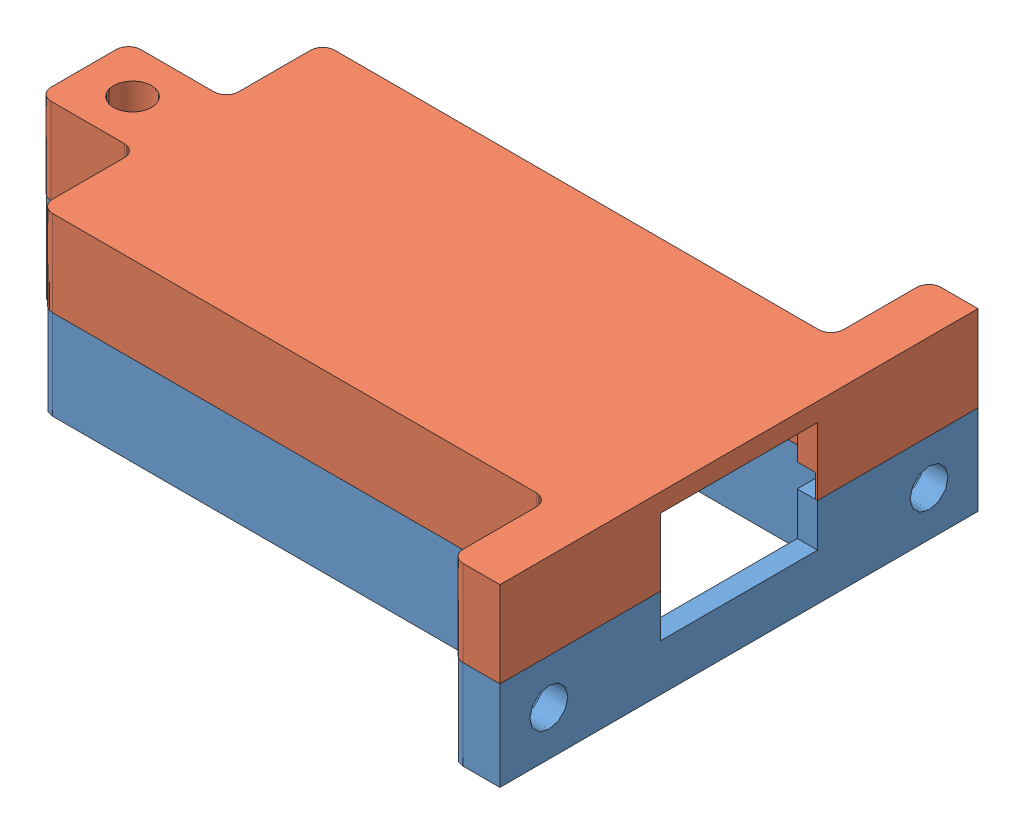
SolidWorks assembly Ensamblaje Caja Arduino_v2, configuration Default. Lengths in mm.
Overall size (53.37 14.3 38.93).
2 component instances, 2 part files, 4 mates.
Components (placement in the parent):
- Base Arduino Nano_v2-1: Base Arduino Nano_v2 [Default] at origin size (53.37 9.8 38.93)
- Tapa arduino Nano_v2-1: Tapa arduino Nano_v2 [Predeterminado] at (0 7.3 0) x (1 0 0) z (0 1 0) size (53.37 38.93 7)
Mates (geometry in assembly coordinates):
- EnPosición1: in place: plane of Base Arduino Nano_v2-1 through (0 4 0) normal (0 1 0); plane of ? through (0 4 0) normal (0 1 0); moOrthogonalPlaneRef_w of Base Arduino Nano_v2-1 through (0 4 0) normal (0 1 0); plane of ? through (0 4 0) normal (0 0 -1); plane of Base Arduino Nano_v2-1 through (0 4 0) normal (0 1 0); plane of ? through (0 4 0) normal (1 0 0); plane of Base Arduino Nano_v2-1 through (0 7.3 0) normal (0 1 0); unknown of Tapa arduino Nano_v2-1
- Coincidente1: coincident aligned: plane of Base Arduino Nano_v2-1; plane of Tapa arduino Nano_v2-1
- Coincidente2: coincident aligned: moOrthogonalPlaneRef_w of Base Arduino Nano_v2-1 through (0 7.3 0) normal (0 0 -1); plane of Tapa arduino Nano_v2-1 through (0 7.3 0) normal (0 0 -1)
- Coincidente3: coincident anti-aligned: moOrthogonalPlaneRef_w of Base Arduino Nano_v2-1 through (0 7.3 0) normal (-1 0 0); plane of Tapa arduino Nano_v2-1 through (0 7.3 0) normal (1 0 0)
